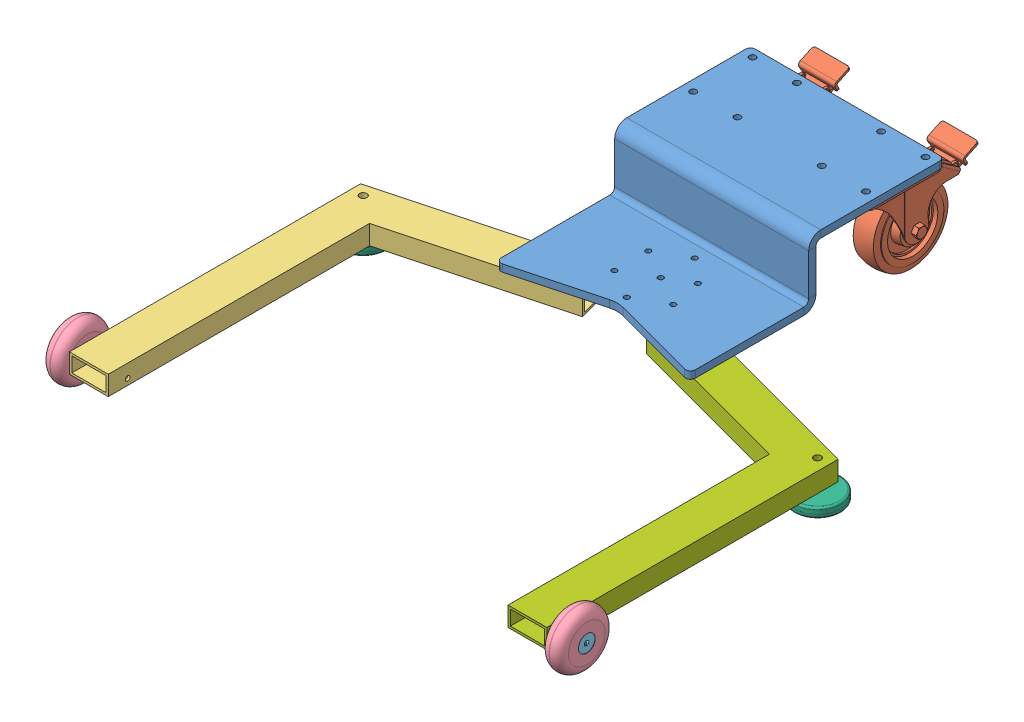
SolidWorks assembly rasm_base_redesignv2, configuration Default. Lengths in mm.
Overall size (678.81 148.07 1022.79).
13 component instances, 7 part files, 21 mates.
Components (placement in the parent):
- rasm_base_plate-1: rasm_base_plate [Default] at (0 47.625 0) size (254 86.11 332.52)
- 27075T720_EASY-ROLL CASTER-1: 27075T720_EASY-ROLL CASTER [27075T72] at (84.1375 124.206 -194.4688) x (0 0 1) z (-1 0 0) size (164.63 125.41 85.72)
- rasm_base_right_leg-2: rasm_base_right_leg [Default] at (-312.42 47.625 270.987) x (-1 0 0) z (0 0 1) size (270.76 25.4 450.03)
- rasm_wheelAssem-2: rasm_wheelAssem [Default] at (-293.1816 86.9234 461.6407) x (-1 0 0) z (0 -0.966148 0.257989) size (25.4 73.02 73.03)
  - rasm_70 mm scooter wheel-1: rasm_70 mm scooter wheel [Default] at (20.8259 39.2832 48.0628) x (0 -1 0) z (0 0 1) size (73.03 25.4 73.03)
  - rasm_Aluminum scooter wheel adapter for 6 mm shaft-1: rasm_Aluminum scooter wheel adapter for 6 mm shaft [Default] at (45.8259 39.2832 48.0628) x (0 -0.801395 -0.598135) z (0 0.598135 -0.801395) size (22 18.5 22)
- rasm_wheelAssem-3: rasm_wheelAssem [Default] at (293.1816 -5.9481 486.4401) x (1 0 0) z (0 0.966148 -0.257989) size (25.4 73.02 73.03)
  - rasm_70 mm scooter wheel-1: rasm_70 mm scooter wheel [Default] at (20.8259 39.2832 48.0628) x (0 -1 0) z (0 0 1) size (73.03 25.4 73.03)
  - rasm_Aluminum scooter wheel adapter for 6 mm shaft-1: rasm_Aluminum scooter wheel adapter for 6 mm shaft [Default] at (45.8259 39.2832 48.0628) x (0 -0.801395 -0.598135) z (0 0.598135 -0.801395) size (22 18.5 22)
- 27075T720_EASY-ROLL CASTER-2: 27075T720_EASY-ROLL CASTER [27075T72] at (-84.1375 124.206 -194.4688) x (0 0 1) z (-1 0 0) size (164.63 125.41 85.72)
- 62805K360_HI-CAP LEVELING MOUNT W  ZINC-PLATED STL STUD-1: 62805K360_HI-CAP LEVELING MOUNT W  ZINC-PLATED STL STUD [62805K36] at (-297.3066 0 92.0839) size (60.96 38.69 60.96)
- 62805K360_HI-CAP LEVELING MOUNT W  ZINC-PLATED STL STUD-2: 62805K360_HI-CAP LEVELING MOUNT W  ZINC-PLATED STL STUD [62805K36] at (297.3066 0 92.0839) x (-1 0 0) z (0 0 -1) size (60.96 38.69 60.96)
- rasm_base_left_leg-1: rasm_base_left_leg [Default] at (-297.18 47.625 270.987) x (-1 0 0) z (0 0 1) size (270.76 25.4 450.03)
Mates (geometry in assembly coordinates):
- Concentric12: concentric aligned: cylinder of ? through (-4008.9055 31.7619 684.2351) axis (0.999991 -0.004196 0) radius 3.048; cylinder of rasm_wheelAssem-2/rasm_Aluminum scooter wheel adapter for 6 mm shaft-1 through (-3894.6065 31.2823 684.2351) axis (0.999991 -0.004196 0) radius 3
- Concentric13: concentric anti-aligned: cylinder of rasm_base_right_leg-2 through (-297.3066 22.225 92.0839) axis (0 1 0) radius 4.7625; circle of 62805K360_HI-CAP LEVELING MOUNT W  ZINC-PLATED STL STUD-1
- Distance3: distance = 9.525 mm anti-aligned: plane of rasm_base_right_leg-2 through (-312.42 22.225 270.987) normal (0 -1 0); plane of 62805K360_HI-CAP LEVELING MOUNT W  ZINC-PLATED STL STUD-1 through (-327.7866 12.7 92.0839) normal (0 1 0)
- Distance8: distance = 6.35 mm aligned: plane of ? through (-4162.0279 44.2425 296.4099) normal (-0.258817 0.001086 0.965926); plane of rasm_base_plate-1
- Coincident42: coincident anti-aligned: plane of ? through (-3894.5568 43.1202 328.6351) normal (0.999991 -0.004196 0); plane of rasm_wheelAssem-2/rasm_Aluminum scooter wheel adapter for 6 mm shaft-1
- Coincident46: coincident anti-aligned: plane of rasm_base_plate-1 through (-127 124.206 -244.475) normal (0 -1 0); plane of 27075T720_EASY-ROLL CASTER-1 through (41.275 124.206 -244.475) normal (0 1 0)
- Coincident47: coincident aligned: plane of rasm_base_plate-1; plane of 27075T720_EASY-ROLL CASTER-1
- Coincident48: coincident anti-aligned: plane of rasm_base_plate-1 through (-4309.0772 131.0131 -2.9009) normal (0 0 -1); plane of 27075T720_EASY-ROLL CASTER-1
- Coincident49: coincident aligned: plane of rasm_base_plate-1 through (-127 133.731 -244.475) normal (0 0 -1); plane of 27075T720_EASY-ROLL CASTER-1 through (41.275 121.8247 -244.475) normal (0 0 -1)
- Coincident50: coincident aligned: plane of rasm_base_plate-1 through (127 133.731 -244.475) normal (1 0 0); plane of 27075T720_EASY-ROLL CASTER-1 through (127 124.206 -244.475) normal (1 0 0)
- Coincident51: coincident anti-aligned: plane of rasm_base_plate-1 through (0 47.625 91.44) normal (0 -1 0); plane of rasm_base_left_leg-1 through (312.42 47.625 270.987) normal (0 1 0)
- Parallel1: parallel anti-aligned: plane of rasm_base_right_leg-2 through (-261.62 22.225 119.4672) normal (1 0 0); plane of rasm_base_left_leg-1 through (261.62 22.225 119.4672) normal (-1 0 0)
- Distance9: distance = 6.35 mm aligned: plane of rasm_base_plate-1 through (127 57.15 89.9699) normal (-0.258819 0 0.965926); plane of rasm_base_left_leg-1 through (41.6596 22.225 60.529) normal (-0.258819 0 0.965926)
- Distance10: distance = 624.84 mm anti-aligned: plane of rasm_base_right_leg-2 through (-312.42 22.225 80.487) normal (-1 0 0); plane of rasm_base_left_leg-1 through (312.42 22.225 80.487) normal (1 0 0)
- Coincident52: coincident anti-aligned: plane of rasm_base_plate-1 through (0 47.625 91.44) normal (0 -1 0); plane of rasm_base_right_leg-2 through (-312.42 47.625 270.987) normal (0 1 0)
- Concentric14: concentric: cylinder of rasm_base_plate-1 through (0 57.15 0) axis (0 1 0) radius 3.3782; point of assembly
- Distance11: distance = 47.625 mm anti-aligned: plane of rasm_base_plate-1 through (0 47.625 91.44) normal (0 -1 0); plane of assembly through (0 0 0) normal (0 1 0)
- Distance12: distance = 6.35 mm aligned: plane of rasm_base_right_leg-2 through (-41.6596 22.225 60.529) normal (0.258819 0 0.965926); plane of rasm_base_plate-1 through (-127 57.15 89.9699) normal (0.258819 0 0.965926)
- Distance15: distance = 312.42 mm aligned: plane of rasm_base_left_leg-1 through (312.42 22.225 80.487) normal (1 0 0); plane of assembly through (0 0 0) normal (1 0 0)
- Concentric15: concentric anti-aligned: cylinder of rasm_base_right_leg-2 through (-198.12 30.353 436.087) axis (-1 0 0) radius 3.048; cylinder of rasm_wheelAssem-2/rasm_Aluminum scooter wheel adapter for 6 mm shaft-1 through (-339.0075 30.353 436.087) axis (1 0 0) radius 3
- Distance16: distance = 1.5875 mm anti-aligned: plane of rasm_wheelAssem-2/rasm_70 mm scooter wheel-1 through (-314.0075 30.353 436.087) normal (1 0 0); plane of rasm_base_right_leg-2 through (-312.42 22.225 80.487) normal (-1 0 0)
